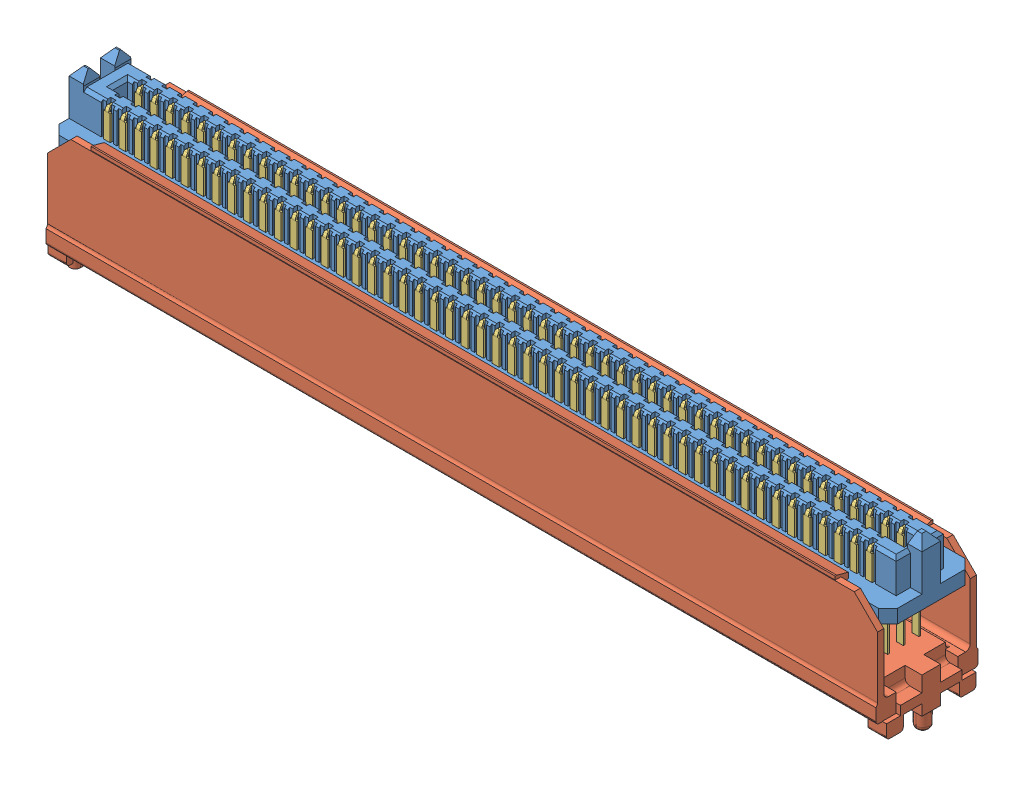
SolidWorks assembly SEAM_50_09_0_L_04_2_A_K_TR, configuration Default. Lengths in mm.
Overall size (68.48 13.87 8.33).
5 component instances, 5 part files, 0 mates.
Components (placement in the parent):
- _SEAM_50_09_0_L_04_1_A_K_TR_body_2-1: _SEAM_50_09_0_L_04_1_A_K_TR_body_2 [Default] at origin size (68.48 6.35 7.06)
- _SEAM_50_09_0_L_04_1_A_K_TR_spacer_4-1: _SEAM_50_09_0_L_04_1_A_K_TR_spacer_4 [Default] at origin size (68.48 11.13 8.33)
- _SEAM_50_09_0_L_04_1_A_K_TR_conn_6-1: _SEAM_50_09_0_L_04_1_A_K_TR_conn_6 [Default] at origin size (67.97 11.29 6.55)
- _SEAM_K_Pad_04_8-1: _SEAM_K_Pad_04_8 [Default] at (0 2.6924 0) size (5.99 0.13 5.99) (hidden)
- _SEAM_Triangle_10-1: _SEAM_Triangle_10 [Default] at (32.2834 1.2954 -1.6764) x (-1 0 0) z (0 0 -1) size (1.02 1.27 0.13)
